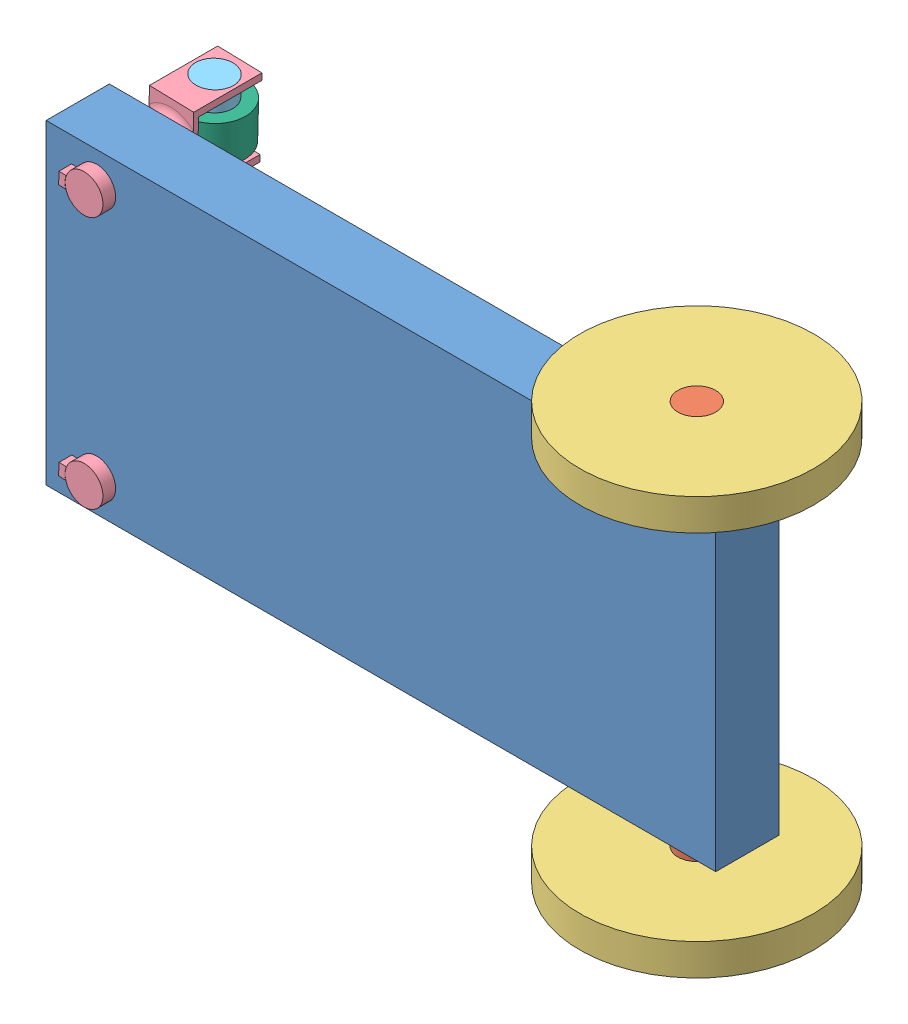
SolidWorks assembly Corrected_coordinate_axis, configuration Default. Lengths in mm.
Overall size (619.21 330 258.42).
11 component instances, 6 part files, 15 mates.
Components (placement in the parent):
- base-1: base [Default] at origin size (530 250 50)
- rear_axle_assembly-1: rear_axle_assembly [Default] at (132.8547 378.4625 233.6752) x (-0.588041 0 -0.808831) z (0 -1 0) size (185 185 330)
  - rear_axle-1: rear_axle [Default] at (134.8184 211.9406 378.4625) size (30 30 330)
  - rear_wheel-1: rear_wheel [Default] at (134.8184 211.9406 530.9625) size (185 185 25)
  - rear_wheel-2: rear_wheel [Default] at (134.8184 211.9406 225.9625) size (185 185 25)
- front_turner-1: front_turner [Default] at (-225 -100 0.77) x (-0.053622 -0.998561 0) z (0 0 -1) size (62 37.5 122.46)
- front_turner-2: front_turner [Default] at (-225 100 0.77) x (-0.026567 -0.999647 0) z (0 0 -1) size (62 37.5 122.46)
- front_wheel_rod-1: front_wheel_rod [Default] at (-225 100 -67.46) x (0.999646 -0.026567 0.001044) z (-0.026567 -0.999647 0) size (30 30 62)
- front_wheel_rod-2: front_wheel_rod [Default] at (-225 -100 -67.46) x (0.998561 -0.053622 0.001044) z (-0.053622 -0.998561 0) size (30 30 62)
- front_wheel-1: front_wheel [Default] at (-225.0001 -100.0027 -67.46) x (-0.998183 0.053602 -0.027519) z (-0.053622 -0.998561 0) size (50 50 30)
- front_wheel-2: front_wheel [Default] at (-225.0001 99.9973 -67.46) x (-0.816664 0.021704 -0.576705) z (0.026567 0.999647 0) size (50 50 30)
Mates (geometry in assembly coordinates):
- Distance3: distance = 10 mm aligned: plane of front_turner-1 through (-225 -100 35) normal (0 0 1); plane of base-1 through (0 0 25) normal (0 0 1)
- Distance4: distance = 10 mm aligned: plane of front_turner-2 through (-225 100 35) normal (0 0 1); plane of base-1 through (0 0 25) normal (0 0 1)
- Concentric4: concentric aligned: cylinder of front_turner-2 through (-227.1519 19.0286 -67.46) axis (0.026567 0.999647 0) radius 15; cylinder of front_wheel_rod-1 through (-225.8236 69.0109 -67.46) axis (0.026567 0.999647 0) radius 15
- Coincident3: coincident aligned: plane of front_turner-2 through (-243.3174 69.4759 -37.46) normal (-0.026567 -0.999647 0); plane of front_wheel_rod-1 through (-225.8236 69.0109 -67.46) normal (-0.026567 -0.999647 0)
- Concentric5: concentric aligned: cylinder of front_turner-1 through (-229.3434 -180.8835 -67.46) axis (0.053622 0.998561 0) radius 15; cylinder of front_wheel_rod-2 through (-226.6623 -130.9554 -67.46) axis (0.053622 0.998561 0) radius 15
- Coincident4: coincident aligned: plane of front_turner-1 through (-244.1371 -130.017 -37.46) normal (-0.053622 -0.998561 0); plane of front_wheel_rod-2 through (-226.6623 -130.9554 -67.46) normal (-0.053622 -0.998561 0)
- Concentric6: concentric aligned: cylinder of front_wheel_rod-2 through (-226.6623 -130.9554 -67.46) axis (0.053622 0.998561 0) radius 15; cylinder of front_wheel-1 through (-231.7029 -224.8229 -67.46) axis (0.053622 0.998561 0) radius 15
- Distance5: distance = 10.7 mm anti-aligned: plane of front_wheel-1 through (-224.1958 -85.0243 -67.46) normal (0.053622 0.998561 0); plane of front_turner-1 through (-241.0969 -73.4013 -87.46) normal (-0.053622 -0.998561 0)
- Concentric7: concentric anti-aligned: cylinder of front_wheel_rod-1 through (-225.8236 69.0109 -67.46) axis (0.026567 0.999647 0) radius 15; cylinder of front_wheel-2 through (-221.6792 224.9531 -67.46) axis (-0.026567 -0.999647 0) radius 15
- Distance6: distance = 10.7 mm anti-aligned: plane of front_wheel-2 through (-224.6016 114.992 -67.46) normal (0.026567 0.999647 0); plane of front_turner-2 through (-241.8111 126.1531 -87.46) normal (-0.026567 -0.999647 0)
- Coincident9: coordinate: unknown of base-1
- Concentric8: concentric anti-aligned: cylinder of base-1 through (225 125 0) axis (0 -1 0) radius 15; cylinder of rear_axle_assembly-1/rear_axle-1 through (225 -165 0) axis (0 1 0) radius 15
- Concentric9: concentric aligned: cylinder of base-1 through (-225 100 -25) axis (0 0 1) radius 15; cylinder of front_turner-2 through (-225 100 -33.46) axis (0 0 1) radius 15
- Concentric10: concentric aligned: cylinder of base-1 through (-225 -100 -25) axis (0 0 1) radius 15; cylinder of front_turner-1 through (-225 -100 -33.46) axis (0 0 1) radius 15
- Distance7: distance = 15 mm anti-aligned: plane of rear_axle_assembly-1/rear_wheel-1 through (225 -140 0) normal (0 1 0); plane of base-1 through (-265 -125 25) normal (0 -1 0)
